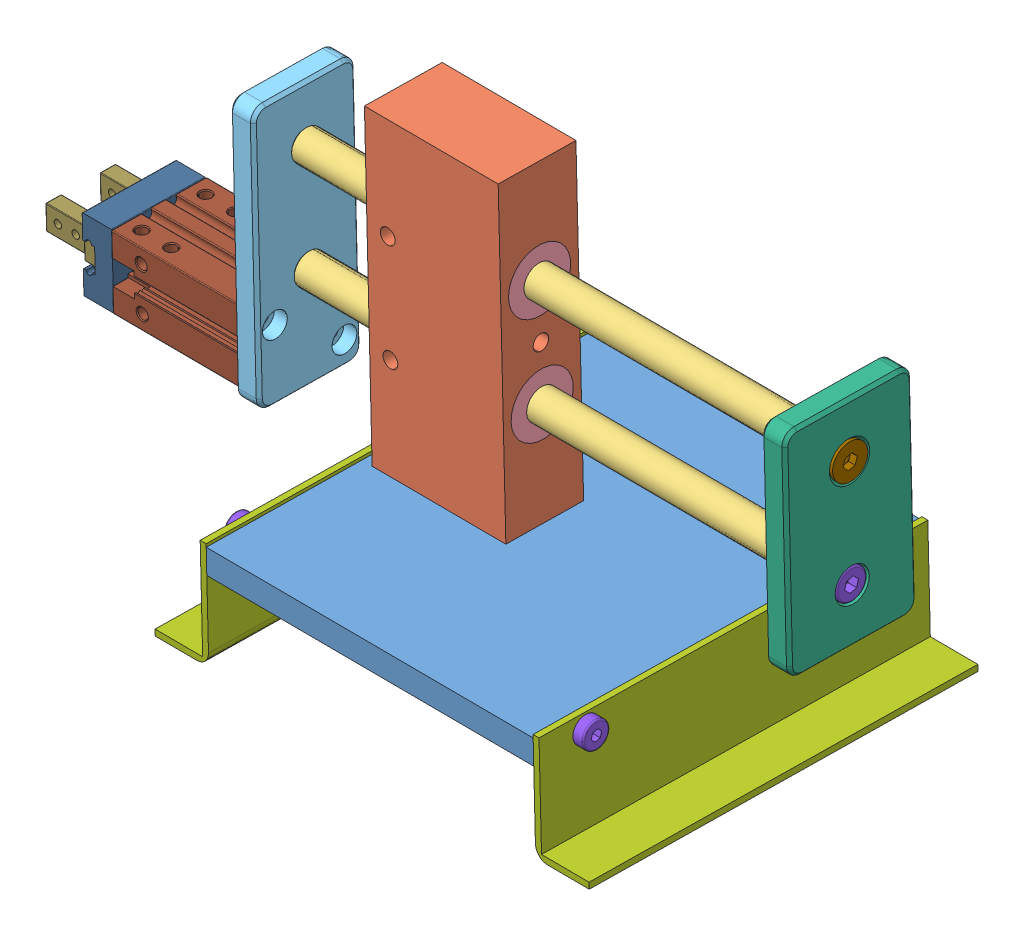
SolidWorks assembly Hoan_thien_cum_lap_rap_s2, configuration Default. Lengths in mm.
Overall size (261.21 137.7 128.52).
27 component instances, 12 part files, 56 mates.
Components (placement in the parent):
- tam de lon-1: tam de lon [Default] at (119.0958 51.1975 54.0073) x (-0.999587 -0.017639 -0.022689) z (-0.022562 -0.007384 0.999718) size (110 8 125)
- con truot s1-2: con truot s1 [Default] at (88.5768 136.6703 53.9498) x (0.999587 0.017639 0.022689) z (0.022562 0.007384 -0.999718) size (45 102 25)
- chot dan huong-1: chot dan huong [Default] at (32.7017 118.182 52.5522) x (0.018497 0.209355 -0.977665) z (0.021995 -0.977681 -0.208942) size (10 175 10)
- chot dan huong-2: chot dan huong [Default] at (33.3248 83.1884 52.3078) x (0.026236 -0.237789 -0.970963) z (0.011731 -0.971157 0.238153) size (10 175 10)
- bac lot-1: bac lot [Default] at (66.3976 118.7766 53.3171) x (0.028076 -0.767933 -0.639915) z (-0.006137 -0.640287 0.768111) size (20 12 20)
- bac lot-2: bac lot [Default] at (67.0207 83.783 53.0727) x (0.018145 -0.999587 -0.022287) z (-0.022287 -0.022689 0.999494) size (20 12 20)
- bac lot-3: bac lot [Default] at (111.379 119.5704 54.3381) x (-0.014484 -0.372719 0.927831) z (0.024823 -0.927776 -0.37231) size (20 12 20)
- bac lot-4: bac lot [Default] at (112.0021 84.5768 54.0937) x (-0.014484 -0.372719 0.927831) z (0.024823 -0.927776 -0.37231) size (20 12 20)
- ban canh truoc-1: ban canh truoc [Default] at (33.1557 92.6867 52.3742) x (-0.022562 -0.007384 0.999718) z (0.017801 -0.999817 -0.006983) size (33 8 86)
- ban canh sau -S1-1: ban canh sau -S1 [Default] at (207.941 103.772 56.4007) x (-0.022562 -0.007384 0.999718) z (-0.017801 0.999817 0.006983) size (41 8 70)
- khoi do-1: khoi do [Default] at (173.7917 36.5109 117.6508) x (0.022562 0.007384 -0.999718) z (-0.999587 -0.017639 -0.022689) size (125 35 18)
- khoi do-2: khoi do [Default] at (64.9414 35.4633 -9.8487) x (-0.022562 -0.007384 0.999718) z (0.999587 0.017639 0.022689) size (125 35 18)
- socket head thin cap screw_din-2: socket head thin cap screw_din [DIN 7984 - M5 x 12 --- 9.6N] at (57.6203 45.7804 100.0932) x (0.999587 0.017639 0.022689) z (-0.022689 -0.0002 0.999743) size (15.5 8.5 8.5)
- socket head thin cap screw_din-3: socket head thin cap screw_din [DIN 7984 - M5 x 12 --- 9.6N] at (59.7637 46.4818 5.12) x (0.999587 0.017639 0.022689) z (-0.022689 -0.0002 0.999743) size (15.5 8.5 8.5)
- socket head thin cap screw_din-4: socket head thin cap screw_din [DIN 7984 - M5 x 12 --- 9.6N] at (180.7137 48.6161 7.8654) x (-0.999587 -0.017639 -0.022689) z (0.022689 -0.968916 -0.246346) size (15.5 8.5 8.5)
- socket head thin cap screw_din-5: socket head thin cap screw_din [DIN 7984 - M5 x 12 --- 9.6N] at (178.5703 47.9147 102.8386) x (-0.999587 -0.017639 -0.022689) z (0.022689 -0.968916 -0.246346) size (15.5 8.5 8.5)
- socket head thin cap screw_din-6: socket head thin cap screw_din [DIN 7984 - M5 x 12 --- 9.6N] at (108.0343 45.1492 61.2151) x (-0.017801 0.999817 0.006983) z (-0.006983 -0.007108 0.99995) size (15.5 8.5 8.5)
- socket head thin cap screw_din-7: socket head thin cap screw_din [DIN 7984 - M5 x 12 --- 9.6N] at (72.3876 44.6249 45.4025) x (-0.017801 0.999817 0.006983) z (-0.006983 -0.007108 0.99995) size (15.5 8.5 8.5)
- socket head thin cap screw_din-9: socket head thin cap screw_din [DIN 7984 - M6 x 14 --- 11N] at (216.0493 86.4128 56.4554) x (-0.999587 -0.017639 -0.022689) z (0.022689 -0.968916 -0.246346) size (18 10 10)
- socket head thin cap screw_din-10: socket head thin cap screw_din [DIN 7984 - M6 x 14 --- 11N] at (25.528 83.0508 52.1308) x (0.999587 0.017639 0.022689) z (-0.022689 -0.0002 0.999743) size (18 10 10)
- socket csink head cap screw 10642_din-2: socket csink head cap screw 10642_din [EN ISO 10642 - M6 x 16 - 16N] at (24.4851 118.037 52.3657) x (0.999587 0.017639 0.022689) z (-0.022678 -0.000819 0.999742) size (16 11.34 11.34)
- socket csink head cap screw 10642_din-3: socket csink head cap screw 10642_din [EN ISO 10642 - M6 x 16 - 16N] at (215.8461 121.4138 56.7094) x (-0.999587 -0.017639 -0.022689) z (0.021761 -0.980227 -0.196676) size (16 11.34 11.34)
- NMHZ2-16D-1: NMHZ2-16D [Default] at (41.1903 62.4231 29.9188) x (-0.022562 -0.007384 0.999718) z (-0.999587 -0.017639 -0.022689) size (30.6 23.6 52.5)
  - NMHZ2-16D Slipway-1: NMHZ2-16D Slipway [Default] at (22.4069 2.6078 57.488) size (30.1 23.6 10)
  - NMHZ2-16D cylinder-2: NMHZ2-16D cylinder [Default] at (22.4069 2.6078 14.988) size (30.6 23.6 42.5)
- NMHZ2-16D air claw-1: NMHZ2-16D air claw [Default] at (-24.8392 63.7045 51.5882) x (-0.022562 -0.007384 0.999718) z (-0.999587 -0.017639 -0.022689) size (12 10 21)
- NMHZ2-16D air claw-2: NMHZ2-16D air claw [Default] at (-24.7838 63.7226 49.1308) x (0.022562 0.007384 -0.999718) z (-0.999587 -0.017639 -0.022689) size (12 10 21)
Mates (geometry in assembly coordinates):
- Parallel5: parallel anti-aligned: plane of tam de lon-1 through (119.0958 51.1975 54.0073) normal (-0.017801 0.999817 0.006983); plane of con truot s1-2 through (90.1077 50.686 53.3493) normal (0.017801 -0.999817 -0.006983)
- Parallel6: parallel anti-aligned: plane of tam de lon-1 through (172.8053 43.7076 117.6817) normal (-0.022562 -0.007384 0.999718); plane of con truot s1-2 through (67.6142 66.3785 40.454) normal (0.022562 0.007384 -0.999718)
- Concentric3: concentric aligned: cylinder of tam de lon-1 through (72.2844 50.4239 45.443) axis (0.017801 -0.999817 -0.006983) radius 2.75; circle of con truot s1-2
- Coincident1: coincident anti-aligned: plane of tam de lon-1 through (119.0958 51.1975 54.0073) normal (-0.017801 0.999817 0.006983); plane of con truot s1-2 through (90.1077 50.686 53.3493) normal (0.017801 -0.999817 -0.006983)
- Concentric4: concentric anti-aligned: cylinder of con truot s1-2 through (41.408 118.3356 52.7498) axis (0.999587 0.017639 0.022689) radius 6; cylinder of chot dan huong-1 through (305.589 122.9974 58.7464) axis (-0.999587 -0.017639 -0.022689) radius 5
- Concentric5: concentric anti-aligned: cylinder of con truot s1-2 through (42.031 83.342 52.5054) axis (0.999587 0.017639 0.022689) radius 6; cylinder of chot dan huong-2 through (306.212 88.0038 58.502) axis (-0.999587 -0.017639 -0.022689) radius 5
- Concentric6: concentric anti-aligned: cylinder of con truot s1-2 through (41.408 118.3356 52.7498) axis (0.999587 0.017639 0.022689) radius 6; cylinder of bac lot-1 through (78.3927 118.9883 53.5893) axis (-0.999587 -0.017639 -0.022689) radius 6
- Coincident2: coincident anti-aligned: plane of con truot s1-2 through (68.3968 118.8119 53.3624) normal (-0.999587 -0.017639 -0.022689); plane of bac lot-1 through (68.3968 118.8119 53.3624) normal (0.999587 0.017639 0.022689)
- Concentric7: concentric anti-aligned: cylinder of con truot s1-2 through (42.031 83.342 52.5054) axis (0.999587 0.017639 0.022689) radius 6; cylinder of bac lot-2 through (79.0157 83.9947 53.3449) axis (-0.999587 -0.017639 -0.022689) radius 6
- Coincident3: coincident anti-aligned: plane of con truot s1-2 through (69.0199 83.8183 53.1181) normal (-0.999587 -0.017639 -0.022689); plane of bac lot-2 through (69.0199 83.8183 53.1181) normal (0.999587 0.017639 0.022689)
- Concentric8: concentric aligned: cylinder of con truot s1-2 through (41.408 118.3356 52.7498) axis (0.999587 0.017639 0.022689) radius 6; cylinder of bac lot-3 through (99.384 119.3587 54.0658) axis (0.999587 0.017639 0.022689) radius 6
- Coincident4: coincident anti-aligned: plane of con truot s1-2 through (109.3799 119.5351 54.2927) normal (0.999587 0.017639 0.022689); plane of bac lot-3 through (109.3799 119.5351 54.2927) normal (-0.999587 -0.017639 -0.022689)
- Concentric9: concentric aligned: cylinder of con truot s1-2 through (42.031 83.342 52.5054) axis (0.999587 0.017639 0.022689) radius 6; cylinder of bac lot-4 through (100.0071 84.3651 53.8214) axis (0.999587 0.017639 0.022689) radius 6
- Coincident5: coincident anti-aligned: plane of con truot s1-2 through (110.0029 84.5415 54.0483) normal (0.999587 0.017639 0.022689); plane of bac lot-4 through (110.0029 84.5415 54.0483) normal (-0.999587 -0.017639 -0.022689)
- Concentric10: concentric aligned: cylinder of chot dan huong-1 through (305.589 122.9974 58.7464) axis (-0.999587 -0.017639 -0.022689) radius 5; cylinder of ban canh truoc-1 through (32.7017 118.182 52.5522) axis (-0.999587 -0.017639 -0.022689) radius 3.3
- Concentric11: concentric aligned: cylinder of chot dan huong-2 through (306.212 88.0038 58.502) axis (-0.999587 -0.017639 -0.022689) radius 5; cylinder of ban canh truoc-1 through (33.3248 83.1884 52.3078) axis (-0.999587 -0.017639 -0.022689) radius 3.3
- Coincident6: coincident anti-aligned: plane of chot dan huong-1 through (32.7017 118.182 52.5522) normal (-0.999587 -0.017639 -0.022689); plane of ban canh truoc-1 through (33.1557 92.6867 52.3742) normal (0.999587 0.017639 0.022689)
- Coincident7: coincident anti-aligned: plane of chot dan huong-2 through (33.3248 83.1884 52.3078) normal (-0.999587 -0.017639 -0.022689); plane of ban canh truoc-1 through (33.1557 92.6867 52.3742) normal (0.999587 0.017639 0.022689)
- Concentric12: concentric anti-aligned: cylinder of chot dan huong-1 through (305.589 122.9974 58.7464) axis (-0.999587 -0.017639 -0.022689) radius 5; cylinder of ban canh sau -S1-1 through (207.6295 121.2688 56.5228) axis (0.999587 0.017639 0.022689) radius 3.3
- Concentric13: concentric anti-aligned: cylinder of chot dan huong-2 through (306.212 88.0038 58.502) axis (-0.999587 -0.017639 -0.022689) radius 5; cylinder of ban canh sau -S1-1 through (208.2525 86.2752 56.2785) axis (0.999587 0.017639 0.022689) radius 3.3
- Coincident8: coincident anti-aligned: plane of chot dan huong-1 through (207.6295 121.2688 56.5228) normal (0.999587 0.017639 0.022689); plane of ban canh sau -S1-1 through (207.941 103.772 56.4007) normal (-0.999587 -0.017639 -0.022689)
- Coincident9: coincident anti-aligned: plane of chot dan huong-2 through (208.2525 86.2752 56.2785) normal (0.999587 0.017639 0.022689); plane of ban canh sau -S1-1 through (207.941 103.772 56.4007) normal (-0.999587 -0.017639 -0.022689)
- Parallel7: parallel aligned: plane of tam de lon-1 through (65.671 42.6903 -9.7789) normal (-0.999587 -0.017639 -0.022689); plane of khoi do-1 through (176.0884 18.6354 -7.4646) normal (-0.999587 -0.017639 -0.022689)
- Parallel8: parallel aligned: plane of tam de lon-1 through (119.0958 51.1975 54.0073) normal (-0.017801 0.999817 0.006983); plane of khoi do-1 through (175.4654 53.629 -7.2202) normal (-0.017801 0.999817 0.006983)
- Concentric14: concentric aligned: cylinder of tam de lon-1 through (160.2221 48.2545 7.4003) axis (0.999587 0.017639 0.022689) radius 2.5; cylinder of khoi do-1 through (52.2667 46.3495 4.9498) axis (0.999587 0.017639 0.022689) radius 2.5
- Coincident10: coincident anti-aligned: plane of tam de lon-1 through (175.6256 44.6306 -7.2831) normal (0.999587 0.017639 0.022689); plane of khoi do-1 through (176.0884 18.6354 -7.4646) normal (-0.999587 -0.017639 -0.022689)
- Parallel9: parallel anti-aligned: plane of tam de lon-1 through (65.671 42.6903 -9.7789) normal (-0.999587 -0.017639 -0.022689); plane of khoi do-2 through (63.3136 15.7721 115.0043) normal (0.999587 0.017639 0.022689)
- Parallel10: parallel anti-aligned: plane of tam de lon-1 through (119.0958 51.1975 54.0073) normal (-0.017801 0.999817 0.006983); plane of khoi do-2 through (63.3136 15.7721 115.0043) normal (0.017801 -0.999817 -0.006983)
- Concentric15: concentric aligned: cylinder of tam de lon-1 through (80.2552 46.8434 5.5851) axis (-0.999587 -0.017639 -0.022689) radius 2.5; cylinder of khoi do-2 through (188.2106 48.7484 8.0356) axis (-0.999587 -0.017639 -0.022689) radius 2.5
- Coincident11: coincident anti-aligned: plane of tam de lon-1 through (65.671 42.6903 -9.7789) normal (-0.999587 -0.017639 -0.022689); plane of khoi do-2 through (63.3136 15.7721 115.0043) normal (0.999587 0.017639 0.022689)
- Concentric16: concentric aligned: cylinder of khoi do-2 through (186.0672 48.047 103.0088) axis (-0.999587 -0.017639 -0.022689) radius 2.5; cylinder of socket head thin cap screw_din-2 through (25.8834 45.2204 99.3728) axis (-0.999587 -0.017639 -0.022689) radius 4.25
- Coincident12: coincident anti-aligned: plane of khoi do-2 through (61.2788 17.7365 114.9729) normal (-0.999587 -0.017639 -0.022689); plane of socket head thin cap screw_din-2 through (61.0438 50.0915 100.1718) normal (0.999587 0.017639 0.022689)
- Concentric17: concentric aligned: cylinder of khoi do-2 through (188.2106 48.7484 8.0356) axis (-0.999587 -0.017639 -0.022689) radius 2.5; cylinder of socket head thin cap screw_din-3 through (28.0268 45.9218 4.3996) axis (-0.999587 -0.017639 -0.022689) radius 4.25
- Coincident13: coincident anti-aligned: plane of khoi do-2 through (61.2788 17.7365 114.9729) normal (-0.999587 -0.017639 -0.022689); plane of socket head thin cap screw_din-3 through (63.1872 50.7929 5.1986) normal (0.999587 0.017639 0.022689)
- Concentric18: concentric aligned: cylinder of khoi do-1 through (52.2667 46.3495 4.9498) axis (0.999587 0.017639 0.022689) radius 2.5; cylinder of socket head thin cap screw_din-4 through (212.4506 49.1762 8.5858) axis (0.999587 0.017639 0.022689) radius 4.25
- Coincident14: coincident anti-aligned: plane of khoi do-1 through (178.052 20.6703 -7.4053) normal (0.999587 0.017639 0.022689); plane of socket head thin cap screw_din-4 through (177.2901 49.6031 3.6681) normal (-0.999587 -0.017639 -0.022689)
- Concentric19: concentric aligned: cylinder of khoi do-1 through (50.1234 45.6481 99.9231) axis (0.999587 0.017639 0.022689) radius 2.5; cylinder of socket head thin cap screw_din-5 through (210.3072 48.4747 103.559) axis (0.999587 0.017639 0.022689) radius 4.25
- Coincident15: coincident anti-aligned: plane of khoi do-1 through (178.052 20.6703 -7.4053) normal (0.999587 0.017639 0.022689); plane of socket head thin cap screw_din-5 through (175.1467 48.9017 98.6413) normal (-0.999587 -0.017639 -0.022689)
- Concentric20: concentric aligned: cylinder of tam de lon-1 through (107.972 48.6485 61.2395) axis (0.017801 -0.999817 -0.006983) radius 5; cylinder of socket head thin cap screw_din-6 through (108.5995 13.405 60.9934) axis (0.017801 -0.999817 -0.006983) radius 4.25
- Coincident16: coincident anti-aligned: plane of tam de lon-1 through (107.972 48.6485 61.2395) normal (0.017801 -0.999817 -0.006983); plane of socket head thin cap screw_din-6 through (103.7228 48.5731 61.2093) normal (-0.017801 0.999817 0.006983)
- Concentric21: concentric aligned: cylinder of tam de lon-1 through (72.2844 50.4239 45.443) axis (0.017801 -0.999817 -0.006983) radius 2.75; cylinder of socket head thin cap screw_din-7 through (72.9528 12.8807 45.1808) axis (0.017801 -0.999817 -0.006983) radius 4.25
- Coincident17: coincident anti-aligned: plane of tam de lon-1 through (72.3253 48.1243 45.4269) normal (0.017801 -0.999817 -0.006983); plane of socket head thin cap screw_din-7 through (68.0761 48.0489 45.3967) normal (-0.017801 0.999817 0.006983)
- Concentric22: concentric aligned: cylinder of ban canh sau -S1-1 through (212.0509 86.3422 56.3647) axis (0.999587 0.017639 0.022689) radius 5.5; cylinder of socket head thin cap screw_din-9 through (247.7862 86.9728 57.1758) axis (0.999587 0.017639 0.022689) radius 5
- Coincident18: coincident anti-aligned: plane of ban canh sau -S1-1 through (212.0509 86.3422 56.3647) normal (0.999587 0.017639 0.022689); plane of socket head thin cap screw_din-9 through (212.1391 87.576 51.5201) normal (-0.999587 -0.017639 -0.022689)
- Concentric23: concentric aligned: cylinder of ban canh truoc-1 through (29.5264 83.1214 52.2216) axis (-0.999587 -0.017639 -0.022689) radius 5.5; cylinder of socket head thin cap screw_din-10 through (-6.2089 82.4908 51.4105) axis (-0.999587 -0.017639 -0.022689) radius 5
- Coincident19: coincident anti-aligned: plane of ban canh truoc-1 through (29.5264 83.1214 52.2216) normal (-0.999587 -0.017639 -0.022689); plane of socket head thin cap screw_din-10 through (29.4382 88.1206 52.2206) normal (0.999587 0.017639 0.022689)
- Coincident20: coincident aligned: cone of ban canh truoc-1 through (27.9037 118.0973 52.4433) axis (0.999587 0.017639 0.022689); cone of socket csink head cap screw 10642_din-2 through (25.5347 118.0555 52.3895) axis (0.999587 0.017639 0.022689)
- Coincident21: coincident aligned: cone of ban canh sau -S1-1 through (212.4275 121.3535 56.6318) axis (-0.999587 -0.017639 -0.022689); cone of socket csink head cap screw 10642_din-3 through (214.7965 121.3953 56.6855) axis (-0.999587 -0.017639 -0.022689)
- Concentric24: concentric anti-aligned: cylinder of ban canh truoc-1 through (33.2689 72.3092 63.2293) axis (-0.999587 -0.017639 -0.022689) radius 2.25; cylinder of NMHZ2-16D-1/NMHZ2-16D cylinder-2 through (10.2784 71.9035 62.7075) axis (0.999587 0.017639 0.022689) radius 2
- Concentric25: concentric aligned: cylinder of ban canh truoc-1 through (29.6341 57.3967 41.0309) axis (0.999587 0.017639 0.022689) radius 4; cylinder of NMHZ2-16D-1/NMHZ2-16D cylinder-2 through (11.0418 57.0686 40.6089) axis (0.999587 0.017639 0.022689) radius 2
- Coincident22: coincident anti-aligned: plane of ban canh truoc-1 through (25.159 92.5456 52.1926) normal (-0.999587 -0.017639 -0.022689); plane of NMHZ2-16D-1/NMHZ2-16D cylinder-2 through (25.6565 64.6007 51.9975) normal (0.999587 0.017639 0.022689)
- Parallel11: parallel anti-aligned: plane of NMHZ2-16D-1/NMHZ2-16D Slipway-1 through (-22.3158 63.9113 28.4034) normal (-0.999587 -0.017639 -0.022689); plane of NMHZ2-16D air claw-1 through (-23.1108 63.6511 63.6302) normal (0.999587 0.017639 0.022689)
- Concentric26: concentric anti-aligned: cylinder of NMHZ2-16D-1/NMHZ2-16D Slipway-1 through (-24.3862 67.8753 28.3859) axis (-0.022562 -0.007384 0.999718) radius 1; cylinder of NMHZ2-16D air claw-1 through (-25.1812 67.6151 63.6128) axis (0.022562 0.007384 -0.999718) radius 1
- Parallel12: parallel anti-aligned: plane of NMHZ2-16D-1/NMHZ2-16D Slipway-1 through (-22.3158 63.9113 28.4034) normal (-0.999587 -0.017639 -0.022689); plane of NMHZ2-16D air claw-2 through (-22.5138 63.8465 37.1796) normal (0.999587 0.017639 0.022689)
- Concentric27: concentric aligned: cylinder of NMHZ2-16D-1/NMHZ2-16D Slipway-1 through (-24.2438 59.8768 28.3301) axis (-0.022562 -0.007384 0.999718) radius 1; cylinder of NMHZ2-16D air claw-2 through (-24.4418 59.812 37.1063) axis (-0.022562 -0.007384 0.999718) radius 1
- LimitDistance1: limit distance = 96.2902 mm anti-aligned: plane of ban canh sau -S1-1 through (207.941 103.772 56.4007) normal (-0.999587 -0.017639 -0.022689); plane of con truot s1-2 through (112.0316 66.9877 66.468) normal (0.999587 0.017639 0.022689)
